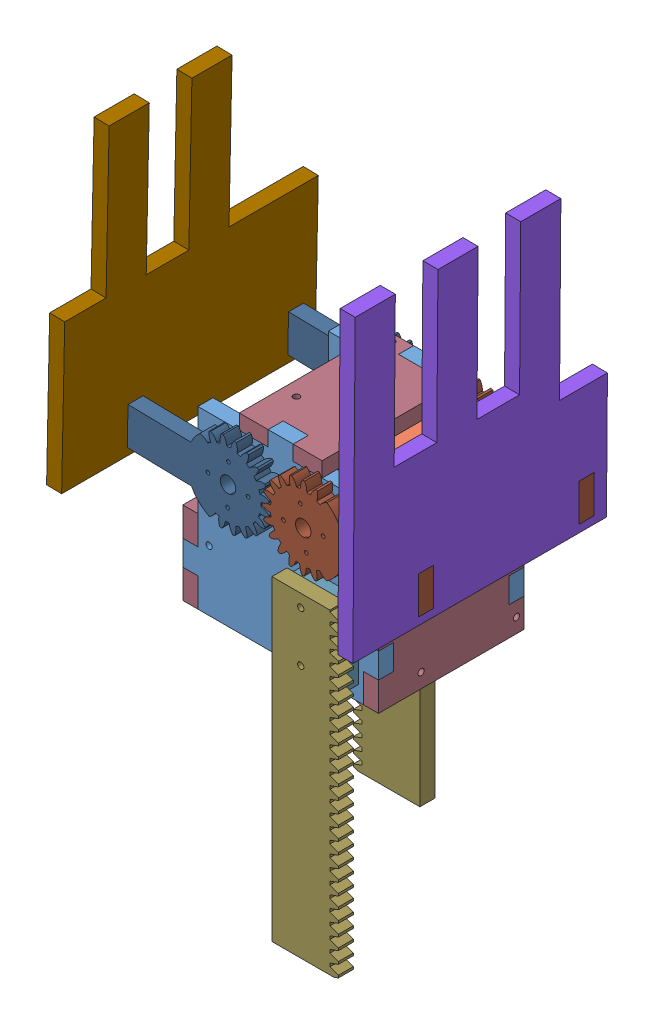
SolidWorks assembly Assemblage Pince, configuration Défaut. Lengths in mm.
Overall size (124.84 252.86 102.1).
35 component instances, 14 part files, 41 mates.
Components (placement in the parent):
- Pièce liaison Pignon Bati-1: Pièce liaison Pignon Bati [Défaut] at (6.5323 25.7104 75.0001) size (78 76 6)
- Pièce liaison Pignon Bati-2: Pièce liaison Pignon Bati [Défaut] at (6.5323 25.7104 133.0001) x (-1 0 0) z (0 0 -1) size (78 76 6)
- AX-12A-1: AX-12A [Default] at (21.5323 25.7104 96.0001) x (0 -1 0) z (0 0 -1) size (50 32 40.55)
  - AX-12A-01-1: AX-12A-01 [Default] at origin size (48.5 26 22)
  - AX-12A-02-1: AX-12A-02 [Default] at (0 0 13.5) size (50 32 8)
  - AX-12A-03-1: AX-12A-03 [Default] at (0 0 -13.5) x (1 0 0) z (0 0 -1) size (50 32 8)
  - AX-12A-04-1: AX-12A-04 [Default] at (0 0 21) size (22 22 6.7)
  - SetScrew-5: SetScrew [Default] at (33 10.4 14.5) x (0.31498 0.949098 0) z (0 0 -1) size (3.3 3.3 29.44)
  - SetScrew-6: SetScrew [Default] at (-9 9.25 14.5) x (0.31498 0.949098 0) z (0 0 -1) size (3.3 3.3 29.44)
  - SetScrew-7: SetScrew [Default] at (-9 -9.25 14.5) x (-0.958559 0.284893 0) z (0 0 -1) size (3.3 3.3 29.44)
  - SetScrew-8: SetScrew [Default] at (33 -10.4 14.5) x (0.31498 0.949098 0) z (0 0 -1) size (3.3 3.3 29.44)
  - pan head cross recess screw_iso-1: pan head cross recess screw_iso [ISO 7045 - M2.5 x 8 - Z --- 8C] at (0 0 21.6) x (0 0 -1) z (1 0 0) size (10.05 5 5)
- AX-12A-2: AX-12A [Default] at (-8.4677 25.7104 112.0001) x (0 -1 0) z (0 0 1) size (50 32 40.55)
  - AX-12A-01-1: AX-12A-01 [Default] at origin size (48.5 26 22)
  - AX-12A-02-1: AX-12A-02 [Default] at (0 0 13.5) size (50 32 8)
  - AX-12A-03-1: AX-12A-03 [Default] at (0 0 -13.5) x (1 0 0) z (0 0 -1) size (50 32 8)
  - AX-12A-04-1: AX-12A-04 [Default] at (0 0 21) size (22 22 6.7)
  - SetScrew-5: SetScrew [Default] at (33 10.4 14.5) x (0.31498 0.949098 0) z (0 0 -1) size (3.3 3.3 29.44)
  - SetScrew-6: SetScrew [Default] at (-9 9.25 14.5) x (0.31498 0.949098 0) z (0 0 -1) size (3.3 3.3 29.44)
  - SetScrew-7: SetScrew [Default] at (-9 -9.25 14.5) x (-0.958559 0.284893 0) z (0 0 -1) size (3.3 3.3 29.44)
  - SetScrew-8: SetScrew [Default] at (33 -10.4 14.5) x (0.31498 0.949098 0) z (0 0 -1) size (3.3 3.3 29.44)
  - pan head cross recess screw_iso-1: pan head cross recess screw_iso [ISO 7045 - M2.5 x 8 - Z --- 8C] at (0 0 21.6) x (0 0 -1) z (1 0 0) size (10.05 5 5)
- Pièce pince facette A-1: Pièce pince facette A [Défaut] at (61.9724 87.5991 124.2676) x (0 0 -1) z (0.999971 -0.007647 0) size (101.1 120 6)
- Pièce pince facette B-1: Pièce pince facette B [Défaut] at (-53.224 88.1958 106.1676) x (0 0 -1) z (0.999793 -0.020337 0) size (101.1 120 6)
- Pignon facette A-1: Pignon facette A [ISO - Spur gear 1.5M 20T 20PA 6FW ---S20A75H50L10.0N] at (-8.4677 25.7104 75.0001) x (0 0 -1) z (0.999793 -0.020337 0) size (6 32.71 62.37)
- Pignon facette A-2: Pignon facette A [ISO - Spur gear 1.5M 20T 20PA 6FW ---S20A75H50L10.0N] at (-8.4677 25.7104 139.0001) x (0 0 -1) z (0.999793 -0.020337 0) size (6 32.71 62.37)
- Pignon facette B-1: Pignon facette B [ISO - Spur gear 1.5M 20T 20PA 6FW ---S20A75H50L10.0N] at (21.5323 25.7104 69) x (0 0 1) z (-0.988856 -0.148877 0) size (6 32.71 62.94)
- Pignon facette B-2: Pignon facette B [ISO - Spur gear 1.5M 20T 20PA 6FW ---S20A75H50L10.0N] at (21.5323 25.7104 133.0001) x (0 0 1) z (-0.988856 -0.148877 0) size (6 32.71 62.94)
- Glissière axe Y-1: Glissière axe Y [ISO - Rack-spur - rectangular 1.5M 20PA 6FW 25PH 150L---SAll] at (-1.9677 8.7104 63.0001) x (0 -1 0) z (0 0 -1) size (126 26.5 6)
- Glissière axe Y-2: Glissière axe Y [ISO - Rack-spur - rectangular 1.5M 20PA 6FW 25PH 150L---SAll] at (15.0323 8.7104 145) x (0 -1 0) z (0 0 1) size (126 26.5 6)
- Pièce renfort-1: Pièce renfort [Défaut] at (6.5323 40.7104 97.0001) x (1 0 0) z (0 1 0) size (33 58 6)
- Pièce renfort-2: Pièce renfort [Défaut] at (45.5323 -12.7896 97.0001) x (0 1 0) z (-1 0 0) size (33 58 6)
- Pièce renfort-3: Pièce renfort [Défaut] at (-32.4677 -12.7896 97.0001) x (0 -1 0) z (1 0 0) size (33 58 6)
- Support Surélève cremaillère-1: Support Surélève cremaillère [Défaut] at (30.8337 -8.6826 133.0001) size (22 30 6)
- Support Surélève cremaillère-2: Support Surélève cremaillère [Défaut] at (-9.1663 -8.6826 69) size (22 30 6)
Mates (geometry in assembly coordinates):
- Coïncidente1: coincident anti-aligned: plane of Pièce liaison Pignon Bati-1 through (21.5323 25.7104 77.0001) normal (0 0 1); plane of AX-12A-1/AX-12A-02-1 through (21.5323 25.7104 77.0001) normal (0 0 -1)
- Coaxiale1: concentric anti-aligned: cylinder of Pièce liaison Pignon Bati-1 through (21.5323 25.7104 81.0001) axis (0 0 -1) radius 10.75; cylinder of AX-12A-1/AX-12A-04-1 through (21.5323 25.7104 75.0001) axis (0 0 1) radius 11
- Parallèle1: parallel anti-aligned: plane of Pièce liaison Pignon Bati-1 through (31.5823 -6.7554 77.0001) normal (-1 0 0); plane of AX-12A-1/AX-12A-01-1 through (34.5323 -9.7896 85) normal (1 0 0)
- Coïncidente3: coincident anti-aligned: plane of Pièce liaison Pignon Bati-2 through (-8.4677 25.7104 131.0001) normal (0 0 -1); plane of AX-12A-2/AX-12A-02-1 through (-8.4677 25.7104 131.0001) normal (0 0 1)
- Coaxiale2: concentric anti-aligned: cylinder of Pièce liaison Pignon Bati-2 through (-8.4677 25.7104 127.0001) axis (0 0 1) radius 10.75; cylinder of AX-12A-2/AX-12A-04-1 through (-8.4677 25.7104 133.0001) axis (0 0 -1) radius 11
- Parallèle2: parallel anti-aligned: plane of Pièce liaison Pignon Bati-2 through (-18.5177 -6.7554 131.0001) normal (1 0 0); plane of AX-12A-2/AX-12A-01-1 through (-21.4677 -9.7896 123.0001) normal (-1 0 0)
- Coïncidente5: coincident aligned: line of Pièce pince facette B-1 through (-54.6398 18.5915 75.0001) axis (0 0 -1); line of Pignon facette A-1 through (-54.6398 18.5915 75.0001) axis (0 0 -1)
- Coïncidente6: coincident aligned: line of Pièce pince facette B-1 through (-54.6398 18.5915 69) axis (0.020337 0.999793 0); line of Pignon facette A-1 through (-54.6398 18.5915 69) axis (0.020337 0.999793 0)
- Coïncidente8: coincident aligned: line of Pièce pince facette B-1 through (-54.6398 18.5915 139.0001) axis (0 0 -1); line of Pignon facette A-2 through (-54.6398 18.5915 139.0001) axis (0 0 -1)
- Coïncidente9: coincident aligned: line of Pièce pince facette B-1 through (-54.6398 18.5915 133.0001) axis (0.020337 0.999793 0); line of Pignon facette A-2 through (-54.6398 18.5915 133.0001) axis (0.020337 0.999793 0)
- Coïncidente15: coincident anti-aligned: plane of Pièce liaison Pignon Bati-1 through (6.5323 25.7104 75.0001) normal (0 0 -1); plane of Pignon facette B-1 through (21.5323 25.7104 75.0001) normal (0 0 1)
- Coïncidente16: coincident anti-aligned: plane of Pièce liaison Pignon Bati-2 through (6.5323 25.7104 133.0001) normal (0 0 1); plane of Pignon facette B-2 through (21.5323 25.7104 133.0001) normal (0 0 -1)
- Coïncidente17: coincident anti-aligned: plane of Pièce liaison Pignon Bati-1 through (6.5323 25.7104 75.0001) normal (0 0 -1); plane of Pignon facette A-1 through (-8.4677 25.7104 75.0001) normal (0 0 1)
- Coïncidente18: coincident anti-aligned: plane of Pièce liaison Pignon Bati-2 through (6.5323 25.7104 133.0001) normal (0 0 1); plane of Pignon facette A-2 through (-8.4677 25.7104 133.0001) normal (0 0 -1)
- Coaxiale3: concentric anti-aligned: cylinder of Pièce liaison Pignon Bati-1 through (-8.4677 25.7104 81.0001) axis (0 0 -1) radius 3.1; cylinder of Pignon facette A-1 through (-8.4677 25.7104 25) axis (0 0 1) radius 3.1
- Coaxiale4: concentric aligned: cylinder of Pièce liaison Pignon Bati-2 through (-8.4677 25.7104 127.0001) axis (0 0 1) radius 10.75; cylinder of Pignon facette A-2 through (-8.4677 25.7104 89) axis (0 0 1) radius 3.1
- Coaxiale5: concentric anti-aligned: cylinder of Pièce liaison Pignon Bati-2 through (21.5323 25.7104 127.0001) axis (0 0 1) radius 3.1; cylinder of Pignon facette B-2 through (21.5323 25.7104 183.0001) axis (0 0 -1) radius 3.1
- Coaxiale6: concentric aligned: cylinder of Pièce liaison Pignon Bati-1 through (21.5323 25.7104 81.0001) axis (0 0 -1) radius 10.75; cylinder of Pignon facette B-1 through (21.5323 25.7104 119.0001) axis (0 0 -1) radius 3.1
- Contr.Engrenages3: gear = 6.2 : 6.2 mm: cylinder of Pignon facette A-1 through (-8.4677 25.7104 25) axis (0 0 1) radius 3.1; cylinder of Pignon facette B-1 through (21.5323 25.7104 119.0001) axis (0 0 -1) radius 3.1
- Coïncidente23: coincident anti-aligned: line of Pièce liaison Pignon Bati-1 through (11.5323 40.7104 75.0001) axis (0 1 0); line of Pièce renfort-1 through (11.5323 46.7104 75.0001) axis (0 -1 0)
- Coïncidente24: coincident aligned: line of Pièce liaison Pignon Bati-1 through (11.5323 46.7104 81.0001) axis (-1 0 0); line of Pièce renfort-1 through (11.5323 46.7104 81.0001) axis (-1 0 0)
- Coïncidente25: coincident anti-aligned: line of Pièce liaison Pignon Bati-1 through (45.5323 -7.7896 75.0001) axis (-1 0 0); line of Pièce renfort-2 through (39.5323 -7.7896 75.0001) axis (1 0 0)
- Coïncidente28: coincident aligned: line of Pièce liaison Pignon Bati-1 through (45.5323 -7.7896 75.0001) axis (0 0 1); line of Pièce renfort-2 through (45.5323 -7.7896 75.0001) axis (0 0 1)
- Coïncidente33: coincident anti-aligned: line of Pièce liaison Pignon Bati-1 through (-32.4677 -7.7896 81.0001) axis (0 -1 0); line of Pièce renfort-3 through (-32.4677 -17.7896 81.0001) axis (0 1 0)
- Coïncidente34: coincident: line of Pièce liaison Pignon Bati-1 through (-32.4677 -17.7896 75.0001) axis (1 0 0); moEndPointRef_w of Pièce renfort-3
- Coïncidente35: coincident anti-aligned: plane of Pièce liaison Pignon Bati-2 through (6.5323 25.7104 133.0001) normal (0 0 1); plane of Support Surélève cremaillère-1 through (30.8337 -8.6826 133.0001) normal (0 0 -1)
- Coaxiale7: concentric anti-aligned: cylinder of Pièce liaison Pignon Bati-2 through (26.5323 3.7104 127.0001) axis (0 0 1) radius 1.4; cylinder of Support Surélève cremaillère-1 through (26.5323 3.7104 139.0001) axis (0 0 -1) radius 1.4
- Coaxiale8: concentric anti-aligned: cylinder of Pièce liaison Pignon Bati-2 through (26.5323 -16.2896 127.0001) axis (0 0 1) radius 1.4; cylinder of Support Surélève cremaillère-1 through (26.5323 -16.2896 139.0001) axis (0 0 -1) radius 1.4
- Coaxiale9: concentric aligned: cylinder of Pièce liaison Pignon Bati-1 through (-13.4677 3.7104 81.0001) axis (0 0 -1) radius 1.4; cylinder of Support Surélève cremaillère-2 through (-13.4677 3.7104 75.0001) axis (0 0 -1) radius 1.4
- Coïncidente37: coincident anti-aligned: plane of Pièce liaison Pignon Bati-1 through (6.5323 25.7104 75.0001) normal (0 0 -1); plane of Support Surélève cremaillère-2 through (-9.1663 -8.6826 75.0001) normal (0 0 1)
- Coaxiale11: concentric aligned: cylinder of Pièce liaison Pignon Bati-1 through (-13.4677 -16.2896 81.0001) axis (0 0 -1) radius 1.4; cylinder of Support Surélève cremaillère-2 through (-13.4677 -16.2896 75.0001) axis (0 0 -1) radius 1.4
- Coïncidente38: coincident anti-aligned: plane of Glissière axe Y-1 through (-28.4677 8.7104 69) normal (0 0 1); plane of Support Surélève cremaillère-2 through (-9.1663 -8.6826 69) normal (0 0 -1)
- Coaxiale12: concentric aligned: cylinder of Glissière axe Y-1 through (-13.4677 3.7104 69) axis (0 0 -1) radius 1.25; cylinder of Support Surélève cremaillère-2 through (-13.4677 3.7104 75.0001) axis (0 0 -1) radius 1.4
- Coaxiale13: concentric aligned: cylinder of Glissière axe Y-1 through (-13.4677 -16.2896 69) axis (0 0 -1) radius 1.25; cylinder of Support Surélève cremaillère-2 through (-13.4677 -16.2896 75.0001) axis (0 0 -1) radius 1.4
- Coïncidente39: coincident anti-aligned: plane of Glissière axe Y-2 through (41.5323 8.7104 139.0001) normal (0 0 -1); plane of Support Surélève cremaillère-1 through (30.8337 -8.6826 139.0001) normal (0 0 1)
- Coaxiale14: concentric anti-aligned: cylinder of Glissière axe Y-2 through (26.5323 3.7104 139.0001) axis (0 0 1) radius 1.25; cylinder of Support Surélève cremaillère-1 through (26.5323 3.7104 139.0001) axis (0 0 -1) radius 1.4
- Coaxiale15: concentric anti-aligned: cylinder of Glissière axe Y-2 through (26.5323 -16.2896 139.0001) axis (0 0 1) radius 1.25; cylinder of Support Surélève cremaillère-1 through (26.5323 -16.2896 139.0001) axis (0 0 -1) radius 1.4
- Coïncidente42: coincident anti-aligned: line of Pièce pince facette A-1 through (67.4399 17.9365 75.0001) axis (0 0 -1); line of Pignon facette B-1 through (67.4399 17.9365 69) axis (0 0 1)
- Coïncidente43: coincident anti-aligned: line of Pièce pince facette A-1 through (67.5546 32.9361 75.0001) axis (-0.007647 -0.999971 0); line of Pignon facette B-1 through (67.4399 17.9365 75.0001) axis (0.007647 0.999971 0)
- Coïncidente44: coincident anti-aligned: line of Pièce pince facette A-1 through (67.4399 17.9365 139.0001) axis (0 0 -1); line of Pignon facette B-2 through (67.4399 17.9365 133.0001) axis (0 0 1)
- Coïncidente45: coincident anti-aligned: line of Pièce liaison Pignon Bati-2 through (45.5323 -7.7896 127.0001) axis (0 -1 0); line of Pièce renfort-2 through (45.5323 -17.7896 127.0001) axis (0 1 0)
